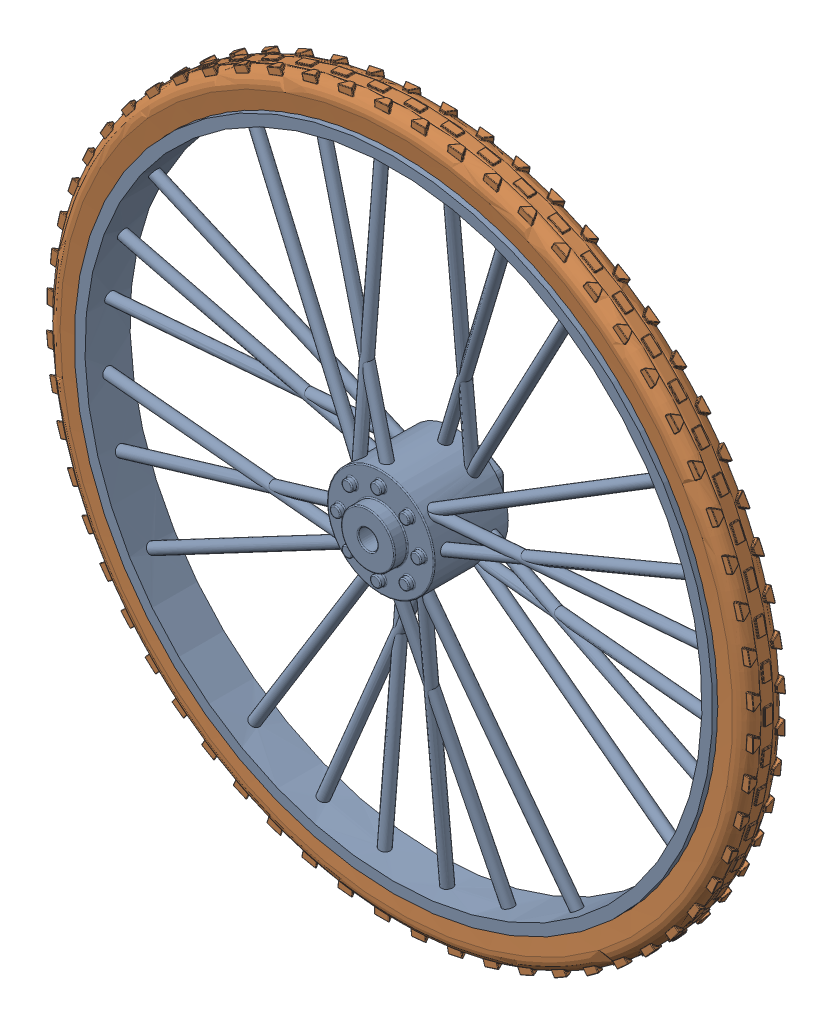
SolidWorks assembly Assem_T_Rear, configuration Default. Lengths in mm.
Overall size (65.93 65.93 10.2).
2 component instances, 2 part files, 6 mates.
Components (placement in the parent):
- 9. rim-1: 9. rim [Default] x (-1 0 0) z (0 1 0) size (63.5 10.7 63.5)
- 10. tyre-1: 10. tyre [Default] x (-1 0 0) z (0 0 -1) size (65.93 65.93 3.67)
Mates (geometry in assembly coordinates):
- Concentric1: concentric aligned: circle of 1. RIM-1; circle of 1. TYRE-1
- Coincident1: coincident anti-aligned: plane of 1. RIM-1 through (0 0 0) normal (0 0 1); plane of 1. TYRE-1 through (0 0 0) normal (0 0 -1)
- Coincident2: coincident aligned: plane of 1. RIM-1 through (0 0 0) normal (0 1 0); plane of 1. TYRE-1 through (0 0 0) normal (0 1 0)
- Coincident3: coincident aligned: plane of 1. RIM-1 through (0 0 0) normal (0 1 0)
- Coincident9: coincident aligned: plane of 1. RIM-1 through (0 0 0) normal (0 0 1)
- Coincident10: coincident anti-aligned: plane of 1. RIM-1 through (0 0 0) normal (-1 0 0)
